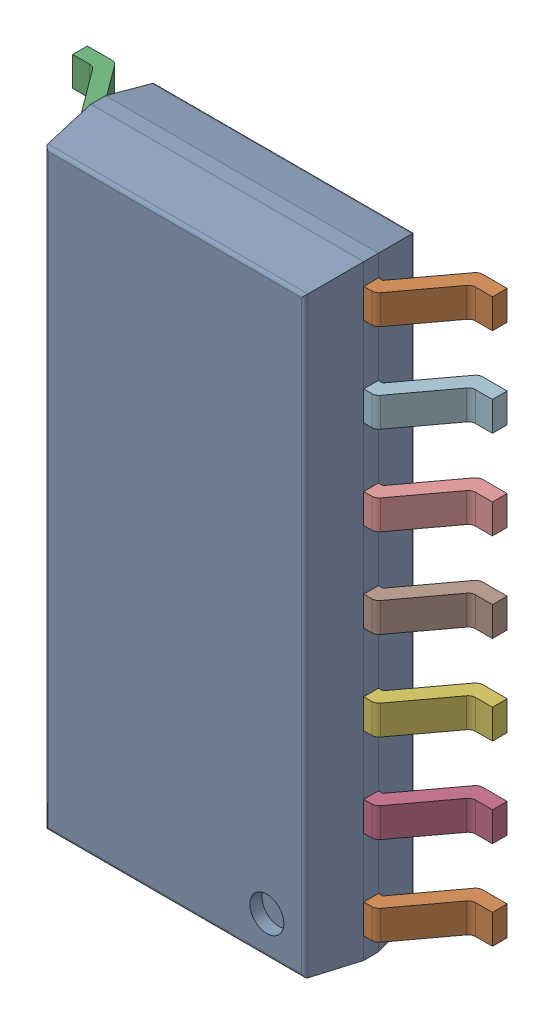
SolidWorks assembly IC11_IC102_1.step, configuration Default. Lengths in mm.
Overall size (6 8.65 1.75).
3 component instances, 2 part files, 0 mates.
Components (placement in the parent):
- 6348793888_1.step-3: 6348793888_1.step [Default] at (521.774 291.943 0) x (-1 0 0) z (0 0 1) size (6 8.65 1.75)
  - Body-16_1.step-14: Body-16_1.step [Default] at origin size (3.9 8.65 1.57)
  - PinsArrayLR-17_1.step-14: PinsArrayLR-17_1.step [Default] at origin size (6 8.04 1)
